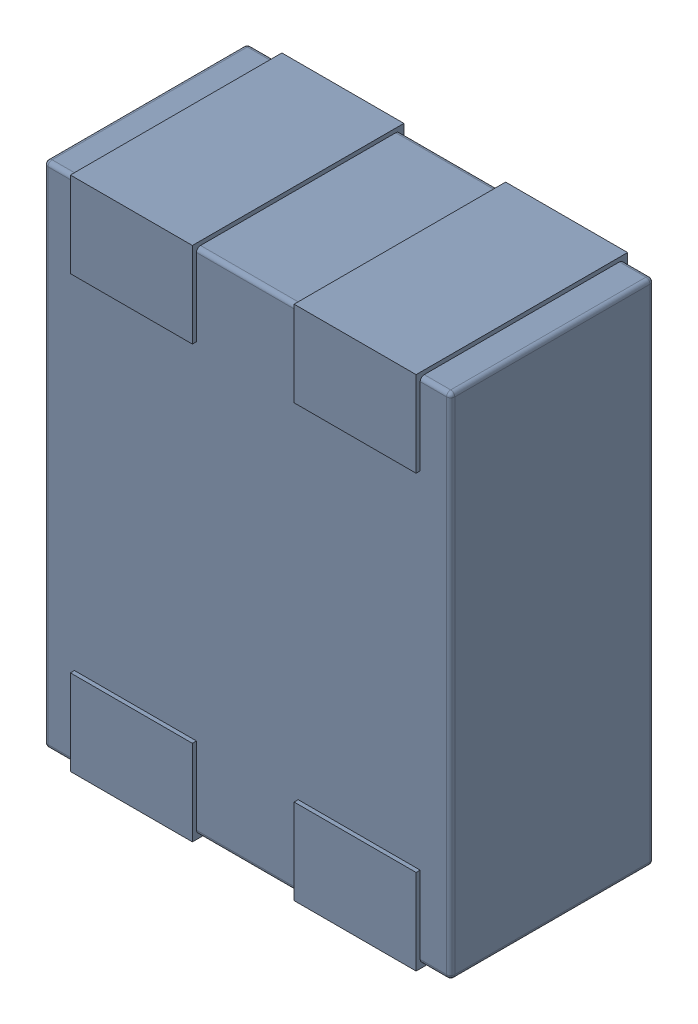
SolidWorks assembly L18, configuration Défaut. Lengths in mm.
Overall size (1 1.27 0.52).
4 component instances, 1 part files, 0 mates.
Components (placement in the parent):
- MCZ1210DH900L2TA0G-1: MCZ1210DH900L2TA0G [Défaut] at (54.9102 -40.4272 -1.6) x (-1 0 0) z (0 0 1) size (1 1.27 0.52)
  - 3D_PCB1_2021-12-30 (1).step-1: 3D_PCB1_2021-12-30 (1).step [Défaut] at origin size (1 1.27 0.52)
    - a3ec64f90eb5404ebd79eca0046a794a.step-1: a3ec64f90eb5404ebd79eca0046a794a.step [Défaut] at (5.0419 -6.8961 1.6) size (1 1.27 0.52)
      - SOLID.step_650-1: SOLID.step_650 [Défaut] at origin size (1 1.27 0.52)
